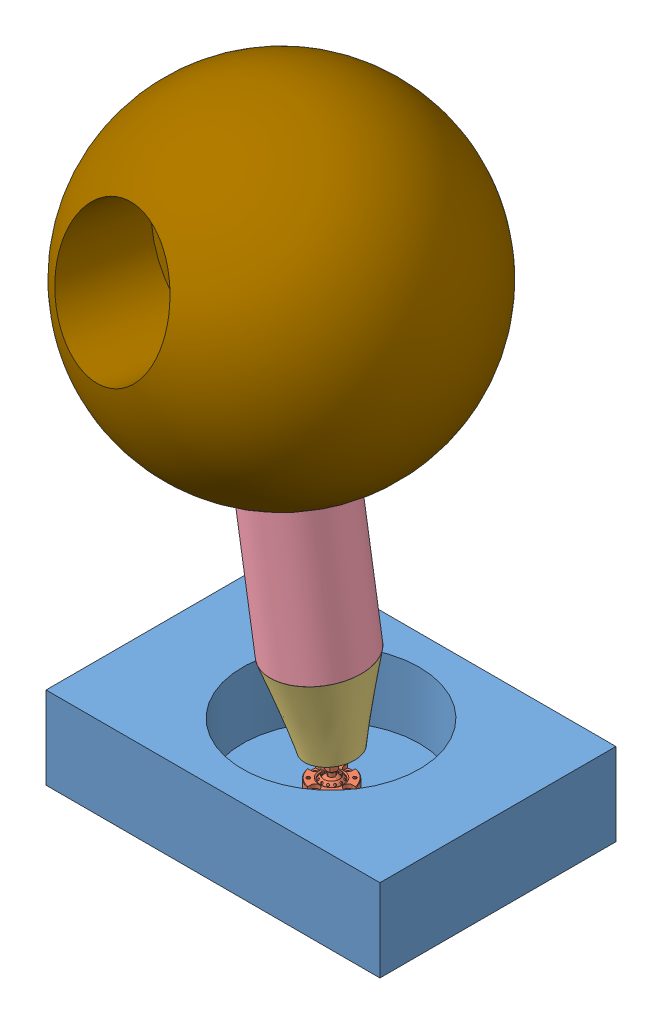
SolidWorks assembly full_model_approx_ball_joints, configuration Default. Lengths in mm.
Overall size (250.57 382.65 240.2).
52 component instances, 9 part files, 21 mates.
Components (placement in the parent):
- torso-1: torso [Default] x (-1 0 0) z (0 0 -1) size (202.29 50 142.99)
- SR JOINT - SRJ006C-1: SR JOINT - SRJ006C [Default] at (0.3693 15.1617 0) x (0 -1 0) z (0 0 1) size (26.94 25.01 25.01)
- cone-1: cone [Default] at (-4.4972 84.3506 2.7072) x (-0.380852 -0.087451 0.920491) z (0.919499 0.068969 0.386994) size (57.45 50 58.36)
- neck-1: neck [Default] at (-14.23 183.7284 8.1216) x (0.186259 0.071629 -0.979886) z (-0.977668 -0.085286 -0.192071) size (55 152.51 55)
- 4200-2: 4200 [Default] at (-2.475 214.8308 12.6296) x (-0.977668 -0.085286 -0.192071) z (0.182609 -0.79711 -0.57556) size (14 30.03 30.03)
  - 4200_3-1: 4200_3 [Default] at (3.5 -8.0902 -5.8779) size (4.76 4.76 4.76)
  - 4200_3-2: 4200_3 [Default] at (3.5 -3.0902 -9.5106) size (4.76 4.76 4.76)
  - 4200_3-3: 4200_3 [Default] at (3.5 3.0902 -9.5106) size (4.76 4.76 4.76)
  - 4200_3-4: 4200_3 [Default] at (3.5 8.0902 -5.8779) size (4.76 4.76 4.76)
  - 4200_3-5: 4200_3 [Default] at (3.5 10 0) size (4.76 4.76 4.76)
  - 4200_3-6: 4200_3 [Default] at (3.5 8.0902 5.8779) size (4.76 4.76 4.76)
  - 4200_3-7: 4200_3 [Default] at (3.5 3.0902 9.5106) size (4.76 4.76 4.76)
  - 4200_3-8: 4200_3 [Default] at (3.5 -3.0902 9.5106) size (4.76 4.76 4.76)
  - 4200_3-9: 4200_3 [Default] at (3.5 -8.0902 5.8779) size (4.76 4.76 4.76)
  - 4200_3-10: 4200_3 [Default] at (3.5 -10 0) size (4.76 4.76 4.76)
  - 4200_3-11: 4200_3 [Default] at (10.5 -8.0902 -5.8779) size (4.76 4.76 4.76)
  - 4200_3-12: 4200_3 [Default] at (10.5 -3.0902 -9.5106) size (4.76 4.76 4.76)
  - 4200_3-13: 4200_3 [Default] at (10.5 3.0902 -9.5106) size (4.76 4.76 4.76)
  - 4200_3-14: 4200_3 [Default] at (10.5 8.0902 -5.8779) size (4.76 4.76 4.76)
  - 4200_3-15: 4200_3 [Default] at (10.5 10 0) size (4.76 4.76 4.76)
  - 4200_3-16: 4200_3 [Default] at (10.5 8.0902 5.8779) size (4.76 4.76 4.76)
  - 4200_3-17: 4200_3 [Default] at (10.5 3.0902 9.5106) size (4.76 4.76 4.76)
  - 4200_3-18: 4200_3 [Default] at (10.5 -3.0902 9.5106) size (4.76 4.76 4.76)
  - 4200_3-19: 4200_3 [Default] at (10.5 -8.0902 5.8779) size (4.76 4.76 4.76)
  - 4200_3-20: 4200_3 [Default] at (10.5 -10 0) size (4.76 4.76 4.76)
  - 4200_24-1: 4200_24 [Default] at (14 0 0) x (-1 0 0) z (0 0 1) size (14 30.03 30.03)
  - 4200_26-1: 4200_26 [Default] at origin size (14 17 17)
- 4200-1: 4200 [Default] at (-18.1391 213.4644 9.5522) x (-0.977668 -0.085286 -0.192071) z (-0.129981 -0.472773 0.871545) size (14 30.03 30.03)
  - 4200_3-1: 4200_3 [Default] at (3.5 -8.0902 -5.8779) size (4.76 4.76 4.76)
  - 4200_3-2: 4200_3 [Default] at (3.5 -3.0902 -9.5106) size (4.76 4.76 4.76)
  - 4200_3-3: 4200_3 [Default] at (3.5 3.0902 -9.5106) size (4.76 4.76 4.76)
  - 4200_3-4: 4200_3 [Default] at (3.5 8.0902 -5.8779) size (4.76 4.76 4.76)
  - 4200_3-5: 4200_3 [Default] at (3.5 10 0) size (4.76 4.76 4.76)
  - 4200_3-6: 4200_3 [Default] at (3.5 8.0902 5.8779) size (4.76 4.76 4.76)
  - 4200_3-7: 4200_3 [Default] at (3.5 3.0902 9.5106) size (4.76 4.76 4.76)
  - 4200_3-8: 4200_3 [Default] at (3.5 -3.0902 9.5106) size (4.76 4.76 4.76)
  - 4200_3-9: 4200_3 [Default] at (3.5 -8.0902 5.8779) size (4.76 4.76 4.76)
  - 4200_3-10: 4200_3 [Default] at (3.5 -10 0) size (4.76 4.76 4.76)
  - 4200_3-11: 4200_3 [Default] at (10.5 -8.0902 -5.8779) size (4.76 4.76 4.76)
  - 4200_3-12: 4200_3 [Default] at (10.5 -3.0902 -9.5106) size (4.76 4.76 4.76)
  - 4200_3-13: 4200_3 [Default] at (10.5 3.0902 -9.5106) size (4.76 4.76 4.76)
  - 4200_3-14: 4200_3 [Default] at (10.5 8.0902 -5.8779) size (4.76 4.76 4.76)
  - 4200_3-15: 4200_3 [Default] at (10.5 10 0) size (4.76 4.76 4.76)
  - 4200_3-16: 4200_3 [Default] at (10.5 8.0902 5.8779) size (4.76 4.76 4.76)
  - 4200_3-17: 4200_3 [Default] at (10.5 3.0902 9.5106) size (4.76 4.76 4.76)
  - 4200_3-18: 4200_3 [Default] at (10.5 -3.0902 9.5106) size (4.76 4.76 4.76)
  - 4200_3-19: 4200_3 [Default] at (10.5 -8.0902 5.8779) size (4.76 4.76 4.76)
  - 4200_3-20: 4200_3 [Default] at (10.5 -10 0) size (4.76 4.76 4.76)
  - 4200_24-1: 4200_24 [Default] at (14 0 0) x (-1 0 0) z (0 0 1) size (14 30.03 30.03)
  - 4200_26-1: 4200_26 [Default] at origin size (14 17 17)
- revolute joint_simple-1: revolute joint_simple [Default] at (-80.7309 212.6121 -4.6783) x (0.175119 0.174654 -0.968932) z (0.977668 0.085286 0.192071) size (11 11 130)
- head2-1: head2 [Default] at (-22.0464 273.3269 8.0664) x (-0.977668 -0.085286 -0.192071) z (-0.081416 0.996288 -0.027965) size (200 200 200)
Mates (geometry in assembly coordinates):
- Concentric15: concentric aligned: circle of cone-1; circle of neck-1
- Coincident33: coincident: unknown of ?; unknown of ?
- Tangent1: tangent: plane of cone-1 through (-97.3859 83.0734 248.7085) normal (-0.014503 0.999837 0.01074); circle of neck-1
- Concentric19: concentric anti-aligned: cylinder of neck-1 through (-94.4819 199.1268 235.6605) axis (-0.30539 -0.014657 0.952115) radius 16; cylinder of 4200-2/4200_24-1 through (-92.7047 199.2121 230.1197) axis (0.30539 0.014657 -0.952115) radius 15
- Concentric20: concentric aligned: cylinder of neck-1 through (-103.6503 198.6868 264.2448) axis (0.30539 0.014657 -0.952115) radius 16; cylinder of 4200-1/4200_24-1 through (-97.8293 198.9662 246.0966) axis (0.30539 0.014657 -0.952115) radius 15
- Concentric23: concentric aligned: circle of neck-1; cylinder of revolute joint_simple-1 through (-69.685 186.0845 191.1886) axis (-0.30539 -0.014657 0.952115) radius 5.5
- Coincident35: coincident anti-aligned: plane of torso-1 through (-89.5053 -2.9961 214.7932) normal (0.20483 -0.032948 -0.978243)
- Coincident36: coincident aligned: plane of torso-1 through (-89.5053 -2.9961 214.7932) normal (-0.042249 0.998204 -0.042467)
- Coincident37: coincident anti-aligned: plane of torso-1 through (-89.5053 -2.9961 214.7932) normal (-0.977885 -0.050029 -0.20307)
- Lock5: lock: unknown of torso-1; unknown of SR JOINT - SRJ006C-1
- Coincident43: coincident aligned: plane of neck-1 through (-94.4819 199.1268 235.6605) normal (0.30539 0.014657 -0.952115); plane of 4200-2/4200_24-1 through (-90.4057 187.9584 230.6838) normal (0.30539 0.014657 -0.952115)
- Coincident44: coincident aligned: plane of neck-1 through (-103.6503 198.6868 264.2448) normal (-0.30539 -0.014657 0.952115); plane of 4200-1/4200_24-1 through (-99.306 185.0608 260.113) normal (-0.30539 -0.014657 0.952115)
- Distance2: distance = 50 mm aligned: plane of revolute joint_simple-1 through (-80.7098 208.0061 -2.7403) normal (-0.977668 -0.085286 -0.192071); plane of neck-1 through (-31.8264 212.2704 6.8632) normal (-0.977668 -0.085286 -0.192071)
- Coincident46: coincident aligned: plane of head2-1 through (-128.458 187.4055 309.5311) normal (0.329022 0.012055 -0.944245); circle of revolute joint_simple-1
- Coincident47: coincident anti-aligned: plane of head2-1 through (-128.458 187.4055 309.5311) normal (0.329022 0.012055 -0.944245); plane of revolute joint_simple-1 through (-109.3856 184.1792 314.9635) normal (-0.30539 -0.014657 0.952115)
- Concentric27: concentric aligned: cylinder of revolute joint_simple-1 through (-69.685 186.0845 191.1886) axis (-0.30539 -0.014657 0.952115) radius 5.5; cylinder of head2-1 through (-85.6852 188.9727 186.7792) axis (-0.329022 -0.012055 0.944245) radius 12
- Coincident48: coincident anti-aligned: unknown of neck-1
- Parallel4: parallel aligned: unknown of neck-1
- Parallel5: parallel anti-aligned: plane of neck-1; plane of head2-1
- LimitAngle5: limit planar angle = 0.111606 rad aligned: plane of cone-1 through (-4.4972 84.3506 2.7072) normal (-0.097328 0.993778 0.054144); plane of torso-1 through (0 60 0) normal (0 1 0)
- LimitAngle7: limit planar angle = 0.083699 rad anti-aligned: plane of head2-1 through (-22.0464 273.3269 8.0664) normal (-0.081416 0.996288 -0.027965); plane of neck-1 through (-14.23 183.7284 8.1216) normal (0.097328 -0.993778 -0.054144)
